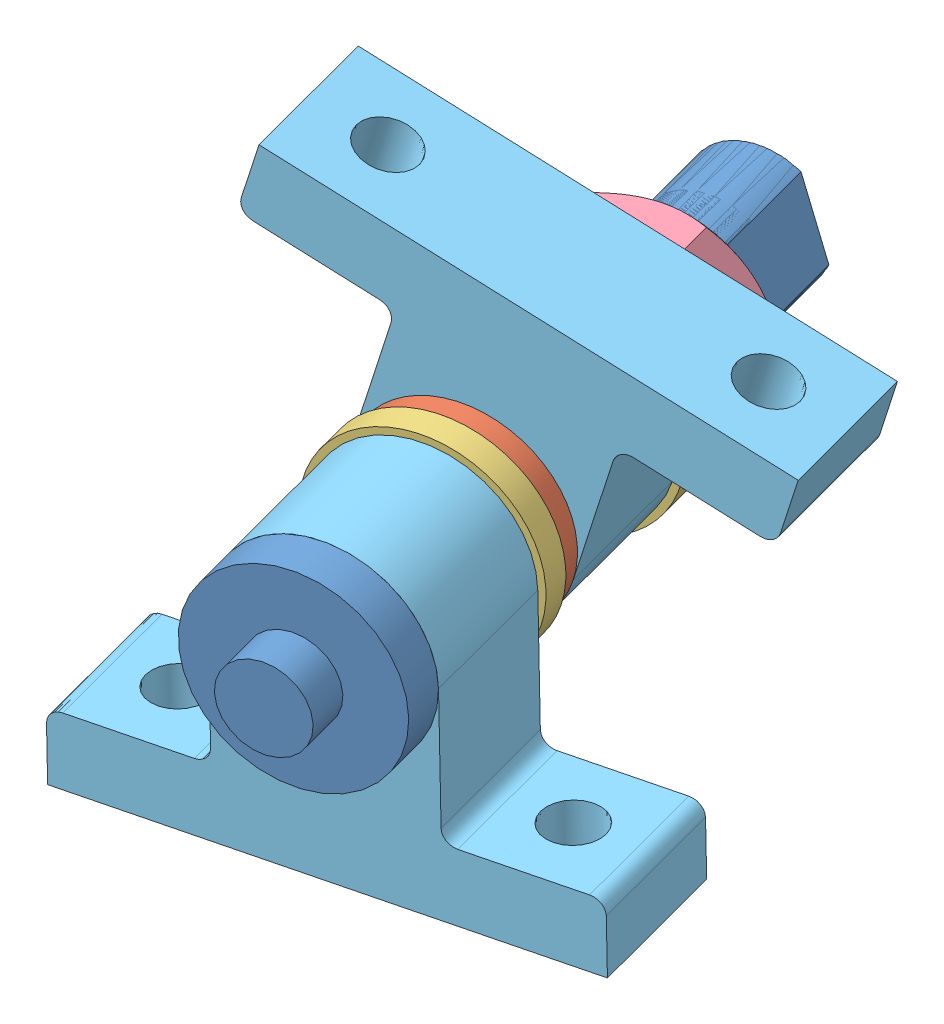
SolidWorks assembly 組合件1, configuration 預設. Lengths in mm.
Overall size (40.16 34.8 52.92).
8 component instances, 5 part files, 14 mates.
Components (placement in the parent):
- 轉軸-1: 轉軸 [預設] at (33.2726 1.4596 67.5463) x (0.240391 -0.023709 0.970387) z (0.27162 -0.958121 -0.090697) size (50 14 14)
- 墊片-1: 墊片 [預設] at (29.9071 1.7915 53.9609) x (0.970672 0.002893 -0.240391) z (0.240391 -0.023709 0.970387) size (14 14 2)
- 彈片-1: 彈片 [預設] at (30.3879 1.7441 55.9016) x (0.970672 0.002893 -0.240391) z (0.240391 -0.023709 0.970387) size (15 15 2)
- 螺絲-1: 螺絲 [螺帽] at (25.0416 2.2714 34.3203) x (0.795961 0.576999 -0.183083) z (0.240391 -0.023709 0.970387) size (14 17.78 6.24)
- 旋轉接頭-1: 旋轉接頭 [預設] at (30.8687 1.6967 57.8424) x (0.970672 0.002893 -0.240391) z (0.240391 -0.023709 0.970387) size (34 22 10)
- 旋轉接頭-2: 旋轉接頭 [預設] at (29.9071 1.7915 53.9609) x (0.929515 -0.282407 -0.237166) z (-0.240391 0.023709 -0.970387) size (34 22 10)
- 墊片-2: 墊片 [預設] at (26.5416 2.1235 40.3755) x (0.962311 -0.12514 -0.241448) z (0.240391 -0.023709 0.970387) size (14 14 2)
- 彈片-2: 彈片 [預設] at (27.0224 2.076 42.3162) x (0.95561 0.181233 -0.232303) z (0.240391 -0.023709 0.970387) size (15 15 2)
Mates (geometry in assembly coordinates):
- 重合/共線/共點1: coincident anti-aligned: circle of 轉軸-1; cylinder of 旋轉接頭-1 through (33.2726 1.4596 67.5463) axis (-0.240391 0.023709 -0.970387) radius 4.5
- 重合/共線/共點2: coincident anti-aligned: plane of 轉軸-1 through (33.2726 1.4596 67.5463) normal (-0.240391 0.023709 -0.970387); plane of 旋轉接頭-1 through (33.2726 1.4596 67.5463) normal (0.240391 -0.023709 0.970387)
- 同軸心1: concentric anti-aligned: cylinder of 轉軸-1 through (33.2726 1.4596 67.5463) axis (0.240391 -0.023709 0.970387) radius 4.5; cylinder of 彈片-1 through (30.8687 1.6967 57.8424) axis (-0.240391 0.023709 -0.970387) radius 4.5
- 同軸心2: concentric anti-aligned: cylinder of 轉軸-1 through (33.2726 1.4596 67.5463) axis (0.240391 -0.023709 0.970387) radius 4.5; cylinder of 墊片-1 through (30.3879 1.7441 55.9016) axis (-0.240391 0.023709 -0.970387) radius 4.5
- 同軸心3: concentric anti-aligned: cylinder of 轉軸-1 through (33.2726 1.4596 67.5463) axis (0.240391 -0.023709 0.970387) radius 4.5; circle of 旋轉接頭-2
- 重合/共線/共點4: coincident aligned: cylinder of 轉軸-1 through (33.2726 1.4596 67.5463) axis (0.240391 -0.023709 0.970387) radius 4.5; circle of 彈片-2
- 同軸心4: concentric anti-aligned: cylinder of 轉軸-1 through (33.2726 1.4596 67.5463) axis (0.240391 -0.023709 0.970387) radius 4.5; cylinder of 墊片-2 through (27.0224 2.076 42.3162) axis (-0.240391 0.023709 -0.970387) radius 4.5
- 同軸心5: concentric anti-aligned: cylinder of 轉軸-1 through (33.2726 1.4596 67.5463) axis (0.240391 -0.023709 0.970387) radius 4.5; cylinder of 螺絲-1 through (25.0416 2.2714 34.3203) axis (-0.240391 0.023709 -0.970387) radius 3.4
- 重合/共線/共點5: coincident anti-aligned: plane of 彈片-1 through (30.8687 1.6967 57.8424) normal (0.240391 -0.023709 0.970387); plane of 旋轉接頭-1 through (30.8687 1.6967 57.8424) normal (-0.240391 0.023709 -0.970387)
- 重合/共線/共點6: coincident anti-aligned: plane of 墊片-1 through (30.3879 1.7441 55.9016) normal (0.240391 -0.023709 0.970387); plane of 彈片-1 through (30.3879 1.7441 55.9016) normal (-0.240391 0.023709 -0.970387)
- 重合/共線/共點7: coincident anti-aligned: plane of 墊片-1 through (29.9071 1.7915 53.9609) normal (-0.240391 0.023709 -0.970387); plane of 旋轉接頭-2 through (29.9071 1.7915 53.9609) normal (0.240391 -0.023709 0.970387)
- 重合/共線/共點8: coincident anti-aligned: plane of 旋轉接頭-2 through (27.5032 2.0286 44.257) normal (-0.240391 0.023709 -0.970387); plane of 彈片-2 through (27.5032 2.0286 44.257) normal (0.240391 -0.023709 0.970387)
- 重合/共線/共點9: coincident anti-aligned: plane of 墊片-2 through (27.0224 2.076 42.3162) normal (0.240391 -0.023709 0.970387); plane of 彈片-2 through (27.0224 2.076 42.3162) normal (-0.240391 0.023709 -0.970387)
- 重合/共線/共點10: coincident anti-aligned: plane of 螺絲-1 through (26.5416 2.1235 40.3755) normal (0.240391 -0.023709 0.970387); plane of 墊片-2 through (26.5416 2.1235 40.3755) normal (-0.240391 0.023709 -0.970387)
